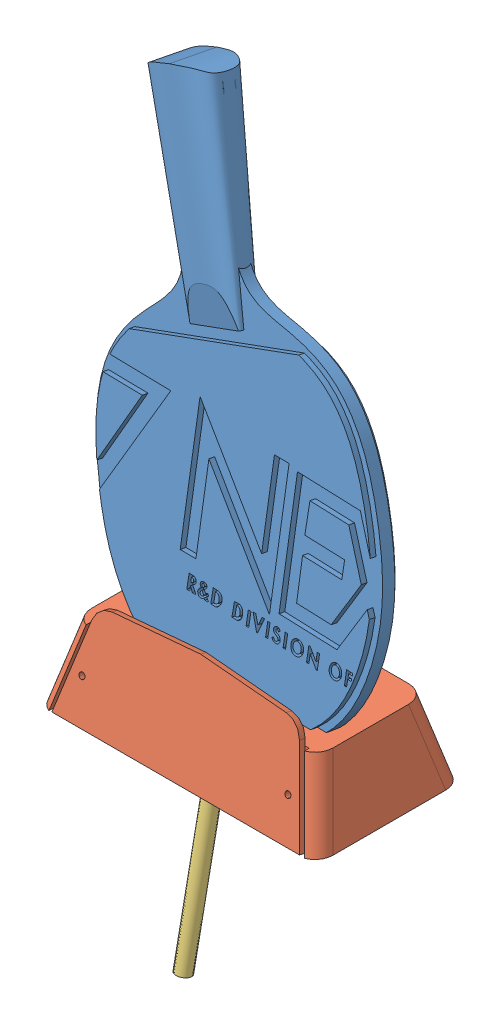
SolidWorks assembly Trophy30, configuration Default. Lengths in mm.
Overall size (237.35 399.5 119.73).
3 component instances, 3 part files, 3 mates.
Components (placement in the parent):
- Paddle10-1: Paddle10 [Default] at (-31.0634 107.4103 -18.5049) x (-0.944615 -0.326975 0.028097) z (-0.029134 0.168824 0.985216) size (156.24 272.12 27.81)
- BaseOriTallPlate10-2: BaseOriTallPlate10 [Default] at (-22.4644 -12.7212 -14.5395) size (150 66.06 79.99)
- ScrewHole^Trophy30-1: ScrewHole^Trophy30 [Default] at (-416.3129 -257.5614 156.7982) x (-0.468791 0.254703 -0.84579) z (-0.645898 0.554317 0.524926) size (63.03 125.41 71.92) (virtual)
Mates (geometry in assembly coordinates):
- Coincident11: coincident anti-aligned: plane of Paddle10-1 through (-21.982 42.4376 -7.1028) normal (-0.024627 -0.985456 0.168137); plane of ScrewHole^Trophy30-1 through (-21.982 42.4376 -7.1028) normal (0.024627 0.985456 -0.168137)
- Concentric4: concentric aligned: cylinder of Paddle10-1 through (-21.982 42.4376 -7.1028) axis (-0.024627 -0.985456 0.168137) radius 1.5; cylinder of ScrewHole^Trophy30-1 through (-21.982 42.4376 -7.1028) axis (-0.024627 -0.985456 0.168137) radius 2.25
- Coincident17: coincident anti-aligned: line of Paddle10-1 through (-62.3586 52.9056 -3.6804) axis (0.999563 0 0.029558); line of BaseOriTallPlate10-2 through (27.4118 52.9056 -1.0258) axis (-0.999563 0 -0.029558)
